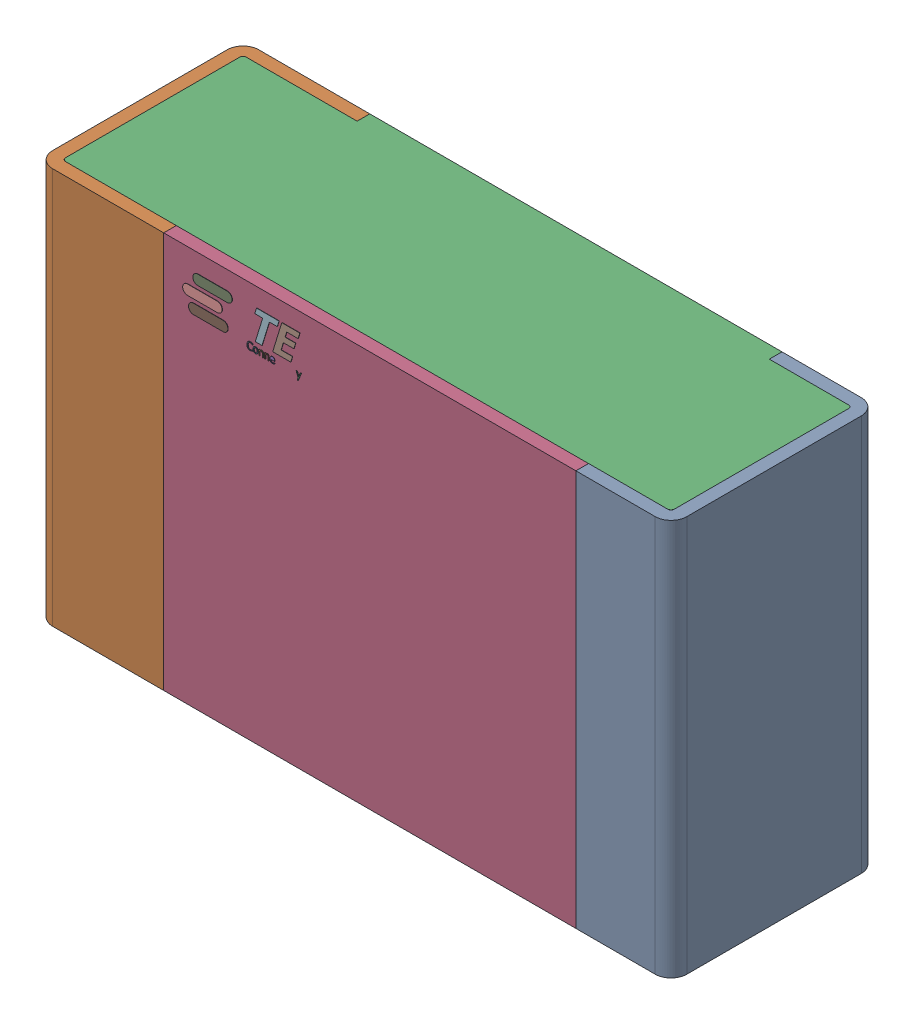
SolidWorks assembly R6.step, configuration Default. Lengths in mm.
Overall size (2 1.25 0.65).
5 component instances, 4 part files, 0 mates.
Components (placement in the parent):
- Res_TE_Connectivity_CPF0805B66R5E1_eec.step-1: Res_TE_Connectivity_CPF0805B66R5E1_eec.step [Default] at (56.841 56.388 0) size (2 1.25 0.65)
  - 1.step-1: 1.step [Default] at origin size (2 1.25 0.65)
  - 2.step-1: 2.step [Default] at origin size (1.92 1.25 0.61)
  - 3.step-1: 3.step [Default] at origin size (1.3 1.25 0.04)
  - TE connectivity Logo 1 (2).step-1: TE connectivity Logo 1 (2).step [Default] at (5.4285 0.313 0.551) x (-1 0 0) z (0 0 1) size (0.37 0.13 0.11)
